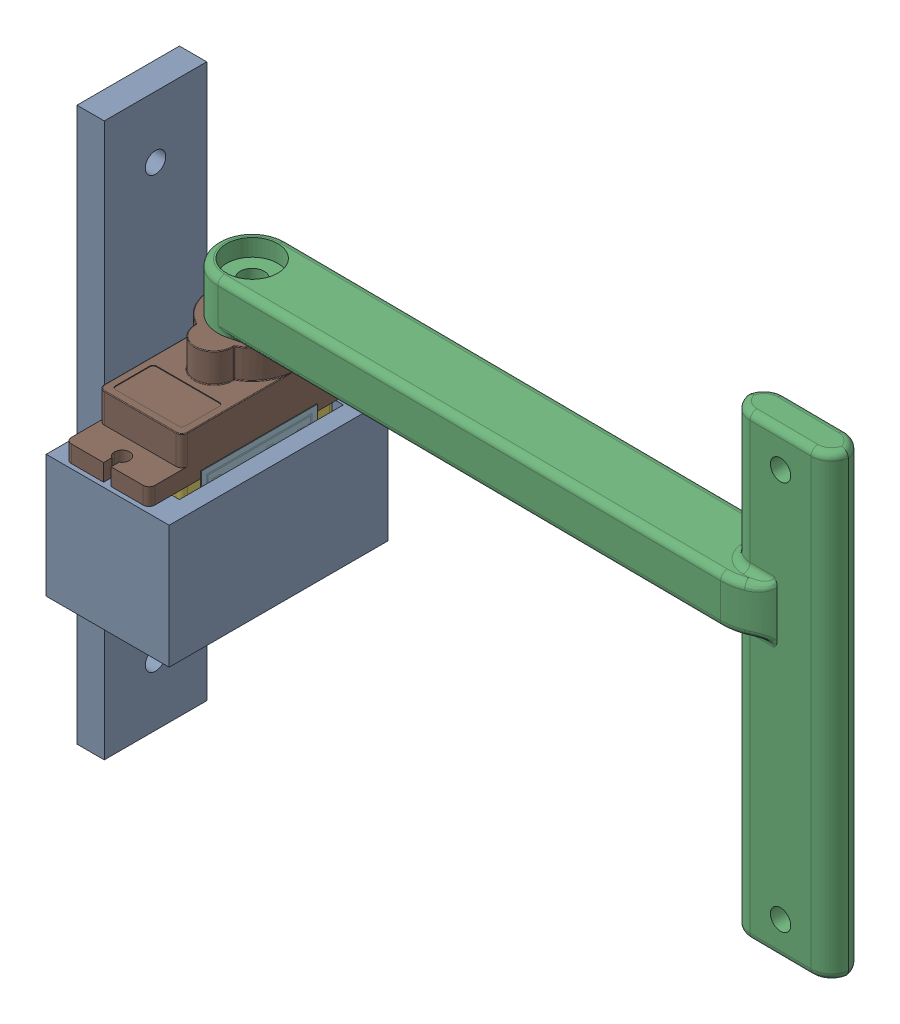
SolidWorks assembly Assemblage_Joute_Solaire, configuration Défaut. Lengths in mm.
Overall size (101.05 81.81 32.1).
3 component instances, 3 part files, 5 mates.
Components (placement in the parent):
- Support_Servo_Horiz-1: Support_Servo_Horiz [Défaut] at (-12.0359 -14.3648 27.1104) x (1 0 0) z (0 1 0) size (22 32 81)
- Servo_SG90-1: Servo_SG90 [Défaut] at (6.7474 -17.6326 4.4371) x (0 0 1) z (-1 0 0) size (32.1 29.95 12.4)
- Bras_Panneau_Solaire_Horiz_Flex_New-1: Bras_Panneau_Solaire_Horiz_Flex_New [Défaut] at (-21.0359 15.3852 5.9604) x (0.999969 0 0.007886) z (0 1 0) size (93.01 10 67.11)
Mates (geometry in assembly coordinates):
- Coïncidente3: coincident anti-aligned: plane of Support_Servo_Horiz-1 through (-12.0359 -11.3648 27.1104) normal (0 1 0); plane of Servo_SG90-1 through (-26.2859 -11.3648 0.7104) normal (0 -1 0)
- Coaxiale4: concentric aligned: cylinder of Support_Servo_Horiz-1 through (-21.0359 -2.3648 25.0104) axis (0 1 0) radius 1.05; cylinder of Servo_SG90-1 through (-21.0359 -11.3648 25.0104) axis (0 1 0) radius 1.1
- Coaxiale5: concentric anti-aligned: circle of Servo_SG90-1; cylinder of Bras_Panneau_Solaire_Horiz_Flex_New-1 through (-21.0359 22.3852 5.9604) axis (0 -1 0) radius 1.75
- Parallèle2: parallel anti-aligned: plane of Support_Servo_Horiz-1 through (-14.5359 3.6352 -0.8896) normal (-1 0 0); plane of Servo_SG90-1 through (-14.9359 6.8352 -4.0896) normal (1 0 0)
- Coïncidente5: coincident anti-aligned: plane of Servo_SG90-1 through (-21.0359 15.3852 5.9604) normal (0 1 0); plane of Bras_Panneau_Solaire_Horiz_Flex_New-1 through (-21.0359 15.3852 5.9604) normal (0 -1 0)
